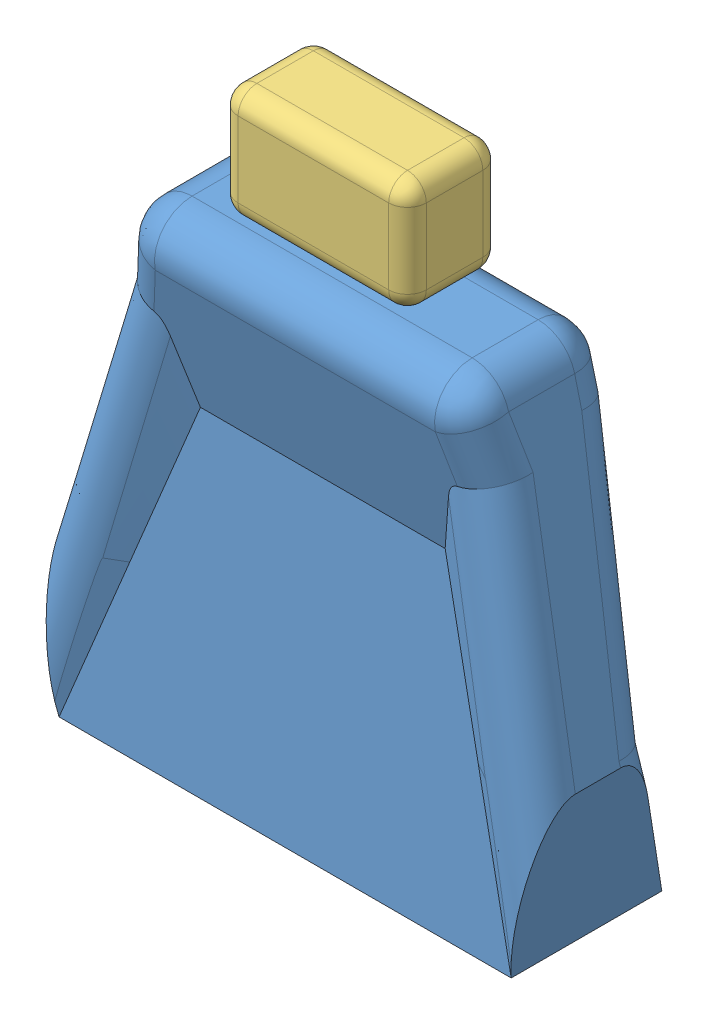
SolidWorks assembly Back Seat and Head Rest Assembly, configuration Default. Lengths in mm.
Overall size (704.87 810.27 273.14).
10 component instances, 5 part files, 5 mates.
Components (placement in the parent):
- Back Seat Assembly-1: Back Seat Assembly [Default] at origin size (704.87 640.09 273.14)
  - Back Seat-1: Back Seat [Default] at origin size (704.87 635.01 273.14)
  - Back Seat Connection-1: Back Seat Connection [Default] at (-50.8 635 101.6) size (30.48 102.87 30.48)
  - Back Seat Connection-2: Back Seat Connection [Default] at (50.8 635 101.6) x (-1 0 0) z (0 0 -1) size (30.48 102.87 30.48)
- Head Rest Assembly-1: Head Rest Assembly [Default] at (0 657.86 101.6) size (254 271.78 127)
  - Head Rest Cushion-1: Head Rest Cushion [Default] at origin size (254 152.4 127)
  - Head Rest Connection-1: Head Rest Connection [Default] at (-50.8 -5.08 0) size (30.48 13.97 30.48)
  - Head Rest Connection-2: Head Rest Connection [Default] at (50.8 -5.08 0) size (30.48 13.97 30.48)
  - Head Rest Rod-1: Head Rest Rod [Default] at (-50.8 -119.38 0) x (-1 0 0) z (0 0 -1) size (5.08 127 5.08)
  - Head Rest Rod-2: Head Rest Rod [Default] at (50.8 -119.38 0) size (5.08 127 5.08)
Mates (geometry in assembly coordinates):
- Coincident1: coordinate: point of Back Seat Assembly-1
- Coincident2: coincident aligned: plane of Back Seat Assembly-1 through (0 0 0) normal (0 1 0)
- Concentric1: concentric: circle of Back Seat Assembly-1/Back Seat Connection-1; circle of Head Rest Assembly-1/Head Rest Rod-1
- Concentric2: concentric: circle of Back Seat Assembly-1/Back Seat Connection-2; circle of Head Rest Assembly-1/Head Rest Rod-2
- Coincident5: coincident aligned: plane of Back Seat Assembly-1/Back Seat Connection-1 through (-50.8 538.48 101.6) normal (0 1 0); circle of Head Rest Assembly-1/Head Rest Rod-1
